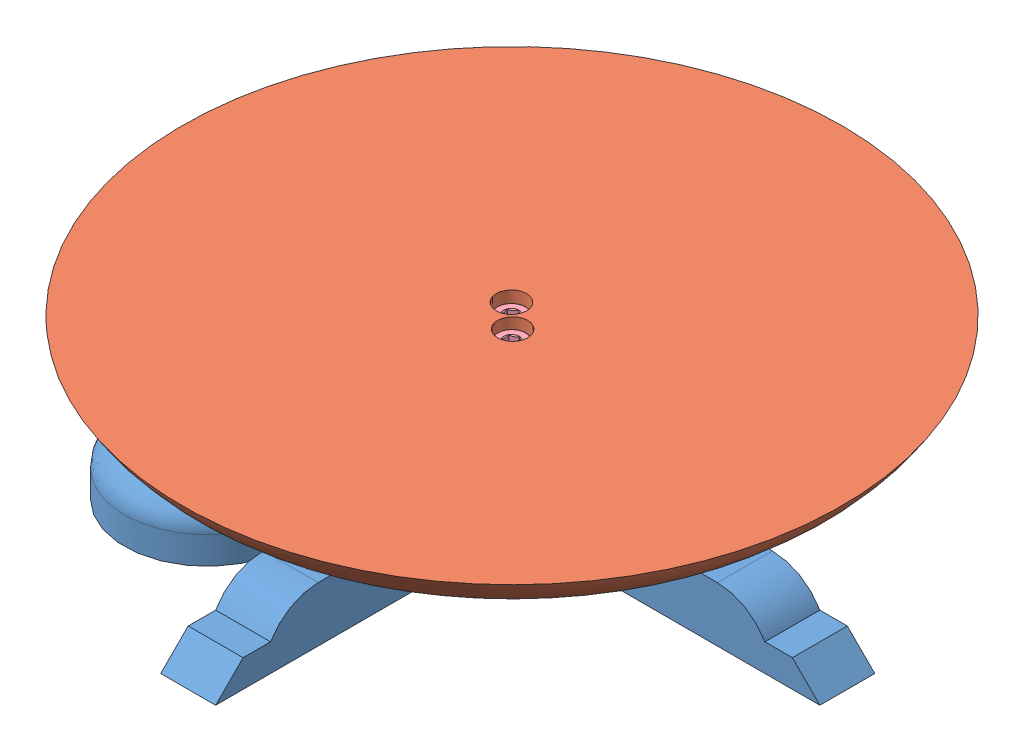
SolidWorks assembly Assem1, configuration Default. Lengths in mm.
Overall size (169.65 28.8 169.65).
7 component instances, 4 part files, 15 mates.
Components (placement in the parent):
- Load Cell Bottom-1: Load Cell Bottom [Default] at (28.8098 46.6052 106.8843) size (120 13.37 120)
- Load Cell Top-1: Load Cell Top [Default] at (28.1702 65.4052 107.2822) x (0.725092 0 0.688652) z (-0.688652 0 0.725092) size (120 10 120)
- Load Cell Bar-1: Load Cell Bar [Default] at (14.194 59.6052 121.1184) x (0.707107 0 -0.707107) z (0.707107 0 0.707107) size (46.3 5.99 11.8)
- M3x12_Socket_Stainless_Steel_Screw-1: M3x12_Socket_Stainless_Steel_Screw [92290A117] at (25.9949 65.9052 105.2163) x (-0.989257 0 0.146189) z (0 1 0) size (5.5 5.5 15.34)
- M3x12_Socket_Stainless_Steel_Screw-2: M3x12_Socket_Stainless_Steel_Screw [92290A117] at (30.1039 65.9052 109.3097) x (1 0 0) z (0 1 0) size (5.5 5.5 15.34)
- M3x12_Socket_Stainless_Steel_Screw-5: M3x12_Socket_Stainless_Steel_Screw [92290A117] at (2.3853 61.1052 137.0283) x (1 0 0) z (0 -1 0) size (5.5 5.5 15.34)
- M3x12_Socket_Stainless_Steel_Screw-6: M3x12_Socket_Stainless_Steel_Screw [92290A117] at (-1.386 61.1052 133.2571) x (1 0 0) z (0 -1 0) size (5.5 5.5 15.34)
Mates (geometry in assembly coordinates):
- Coincident1: coincident anti-aligned: line of Load Cell Bottom-1 through (2.3853 56.6052 137.0283) axis (0 -1 0); line of Load Cell Bar-1 through (2.3853 59.6052 137.0283) axis (0 1 0)
- Parallel1: parallel anti-aligned: line of Load Cell Bottom-1 through (-1.386 56.6052 133.2571) axis (0 -1 0); line of Load Cell Bar-1 through (-1.7159 59.6052 132.9271) axis (0 1 0)
- Coincident3: coincident anti-aligned: plane of Load Cell Bottom-1 through (28.8098 59.6052 106.8843) normal (0 1 0); plane of Load Cell Bar-1 through (14.194 59.6052 121.1184) normal (0 -1 0)
- Parallel2: parallel: line of Load Cell Bottom-1 through (1.6073 59.6052 142.5204) axis (0.707107 0 -0.707107); plane of Load Cell Bar-1 through (18.3659 65.4052 125.2904) normal (0.707107 0 0.707107)
- Coincident5: coincident anti-aligned: line of Load Cell Top-1 through (25.9949 70.4052 105.2163) axis (0 -1 0); line of Load Cell Bar-1 through (25.9949 59.6052 105.2163) axis (0 1 0)
- Parallel3: parallel anti-aligned: line of Load Cell Top-1 through (30.3455 70.4052 109.3482) axis (0 -1 0); line of Load Cell Bar-1 through (30.1039 59.6052 109.3097) axis (0 1 0)
- Coincident7: coincident anti-aligned: plane of Load Cell Top-1 through (28.1702 65.4052 107.2822) normal (0 -1 0); plane of Load Cell Bar-1 through (14.194 65.4052 121.1184) normal (0 1 0)
- Coincident10: coincident aligned: line of Load Cell Bar-1 through (25.9949 59.6052 105.2163) axis (0 1 0); line of M3x12_Socket_Stainless_Steel_Screw-1 through (25.9949 58.7299 105.2163) axis (0 1 0)
- Coincident12: coincident anti-aligned: plane of Load Cell Top-1 through (25.9949 70.4052 105.2163) normal (0 1 0); plane of M3x12_Socket_Stainless_Steel_Screw-1 through (26.2142 70.4052 106.7001) normal (0 -1 0)
- Coincident13: coincident aligned: line of Load Cell Bar-1 through (30.1039 59.6052 109.3097) axis (0 1 0); line of M3x12_Socket_Stainless_Steel_Screw-2 through (30.1039 58.7299 109.3097) axis (0 1 0)
- Coincident14: coincident anti-aligned: plane of Load Cell Top-1 through (30.3455 70.4052 109.3482) normal (0 1 0); plane of M3x12_Socket_Stainless_Steel_Screw-2 through (30.1039 70.4052 107.8097) normal (0 -1 0)
- Coincident15: coincident: line of assembly; line of assembly; axis of Load Cell Bottom-1 through (-1.386 56.6052 133.2571) axis (0 -1 0); axis of M3x12_Socket_Stainless_Steel_Screw-6 through (-1.386 68.2804 133.2571) axis (0 -1 0)
- Coincident16: coincident anti-aligned: plane of Load Cell Bottom-1 through (-1.386 56.6052 133.2571) normal (0 -1 0); plane of M3x12_Socket_Stainless_Steel_Screw-6 through (-1.386 56.6052 134.7571) normal (0 1 0)
- Coincident17: coincident: line of assembly; line of assembly; axis of Load Cell Bottom-1 through (2.3853 56.6052 137.0283) axis (0 -1 0); axis of M3x12_Socket_Stainless_Steel_Screw-5 through (2.3853 68.2804 137.0283) axis (0 -1 0)
- Coincident18: coincident anti-aligned: plane of Load Cell Bottom-1 through (2.3853 56.6052 137.0283) normal (0 -1 0); plane of M3x12_Socket_Stainless_Steel_Screw-5 through (2.3853 56.6052 138.5283) normal (0 1 0)
